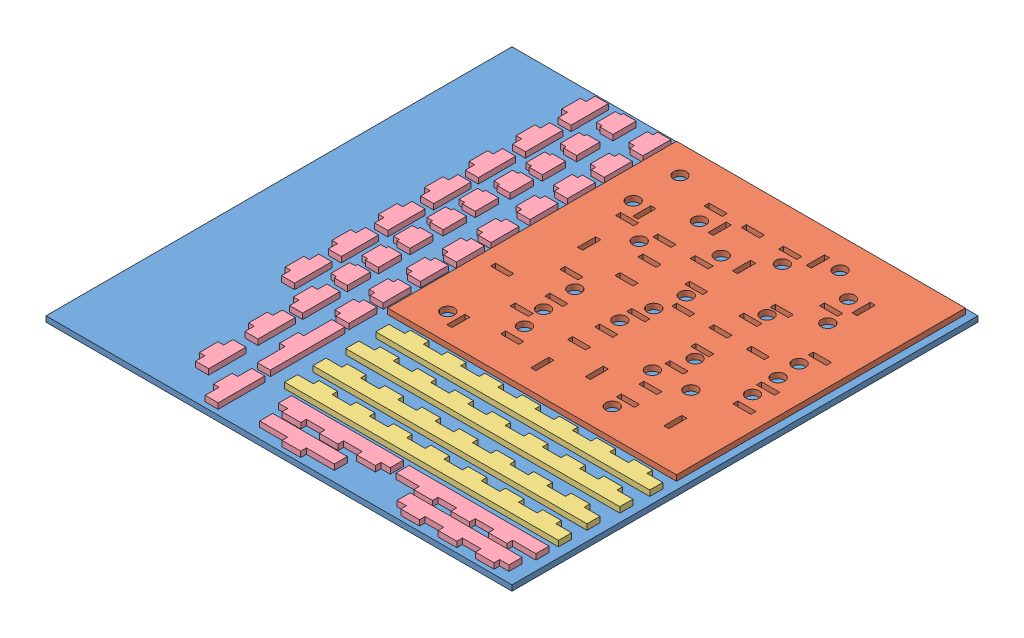
SolidWorks assembly Layout_Assly, configuration Default. Lengths in mm.
Overall size (500 12 500).
40 component instances, 4 part files, 44 mates.
Components (placement in the parent):
- Part2-1: Part2 [Default] at origin size (500 6 500)
- BasePlate-1: BasePlate [Default] at (492.029 6 -494.4537) x (-1 0 0) z (0 0 -1) size (310 6 310)
- SIdePlate-1: SIdePlate [Default] at (344.8244 12 -170.014) x (1 0 0) z (0 -1 0) size (294 20 6)
- SIdePlate-2: SIdePlate [Default] at (344.2023 12 -138.4405) x (1 0 0) z (0 -1 0) size (294 20 6)
- SIdePlate-3: SIdePlate [Default] at (342.5749 12 -104.9025) x (1 0 0) z (0 -1 0) size (294 20 6)
- SIdePlate-4: SIdePlate [Default] at (342.6836 12 -74.261) x (1 0 0) z (0 -1 0) size (294 20 6)
- Partition-1: Partition [Default] at (163.5434 12 -492.808) x (0 -1 0) z (0 0 1) size (6 20 30)
- Partition-2: Partition [Default] at (162.8997 12 -452.1256) x (0 -1 0) z (0 0 1) size (6 20 30)
- Partition-3: Partition [Default] at (162.8487 12 -412.6126) x (0 -1 0) z (0 0 1) size (6 20 30)
- Partition-4: Partition [Default] at (162.2578 12 -373.1005) x (0 -1 0) z (0 0 1) size (6 20 30)
- Partition-5: Partition [Default] at (162.7722 12 -330.7673) x (0 -1 0) z (0 0 1) size (6 20 30)
- Partition-6: Partition [Default] at (162.2941 12 -294.0403) x (0 -1 0) z (0 0 1) size (6 20 30)
- Partition-7: Partition [Default] at (160.9984 12 -256.6845) x (0 -1 0) z (0 0 1) size (6 20 30)
- Partition-8: Partition [Default] at (160.886 12 -216.9444) x (0 -1 0) z (0 0 1) size (6 20 30)
- Partition-9: Partition [Default] at (161.5652 12 -179.4132) x (0 -1 0) z (0 0 1) size (6 20 30)
- Partition-10: Partition [Width_150mm] at (489.8619 6 -35.7855) x (0 1 0) z (-1 0 0) size (6 20 150)
- Partition-11: Partition [Width_120mm] at (331.87 6 -37.5014) x (0 1 0) z (-1 0 0) size (6 20 120)
- Partition-12: Partition [Width_120mm] at (485.9067 6 -10.8609) x (0 1 0) z (-1 0 0) size (6 20 120)
- Partition-13: Partition [Width_80mm] at (162.858 12 -143.8335) x (0 -1 0) z (0 0 1) size (6 20 80)
- Partition-14: Partition [Width_80mm] at (298.3896 6 -10.9079) x (0 1 0) z (-1 0 0) size (6 20 80)
- Partition-15: Partition [width_50mm] at (165.2881 12 -55.4645) x (0 -1 0) z (0 0 1) size (6 20 50)
- Partition-16: Partition [Width_25mm] at (127.6871 12 -491.5944) x (0 -1 0) z (0 0 1) size (6 20 25)
- Partition-17: Partition [Width_25mm] at (127.7224 12 -452.5904) x (0 -1 0) z (0 0 1) size (6 20 25)
- Partition-18: Partition [Width_25mm] at (127.2263 12 -416.2576) x (0 -1 0) z (0 0 1) size (6 20 25)
- Partition-19: Partition [Width_25mm] at (127.0085 12 -382.0514) x (0 -1 0) z (0 0 1) size (6 20 25)
- Partition-20: Partition [Width_25mm] at (125.1472 12 -346.4351) x (0 -1 0) z (0 0 1) size (6 20 25)
- Partition-21: Partition [Width_25mm] at (125.0837 12 -312.1334) x (0 -1 0) z (0 0 1) size (6 20 25)
- Partition-22: Partition [Width_25mm] at (124.6156 12 -276.8588) x (0 -1 0) z (0 0 1) size (6 20 25)
- Partition-23: Partition [Width_25mm] at (125.4179 12 -242.1872) x (0 -1 0) z (0 0 1) size (6 20 25)
- Partition-24: Partition [Width_25mm] at (125.4406 12 -208.8491) x (0 -1 0) z (0 0 1) size (6 20 25)
- Partition-25: Partition [Width_40mm] at (127.2199 12 -174.1968) x (0 -1 0) z (0 0 1) size (6 20 40)
- Partition-26: Partition [Width_40mm] at (127.3475 12 -126.1339) x (0 -1 0) z (0 0 1) size (6 20 40)
- Partition-27: Partition [Width_40mm] at (96.5799 12 -492.7639) x (0 -1 0) z (0 0 1) size (6 20 40)
- Partition-28: Partition [Width_40mm] at (96.8462 12 -443.668) x (0 -1 0) z (0 0 1) size (6 20 40)
- Partition-29: Partition [Width_40mm] at (95.6032 12 -394.3264) x (0 -1 0) z (0 0 1) size (6 20 40)
- Partition-30: Partition [Width_40mm] at (95.781 12 -346.2225) x (0 -1 0) z (0 0 1) size (6 20 40)
- Partition-31: Partition [Width_40mm] at (96.0529 12 -296.6662) x (0 -1 0) z (0 0 1) size (6 20 40)
- Partition-32: Partition [Width_40mm] at (95.3483 12 -247.5018) x (0 -1 0) z (0 0 1) size (6 20 40)
- Partition-33: Partition [Width_40mm] at (128.4442 12 -72.1397) x (0 -1 0) z (0 0 1) size (6 20 40)
- Partition-34: Partition [Width_40mm] at (95.0635 12 -197.5849) x (0 -1 0) z (0 0 1) size (6 20 40)
Mates (geometry in assembly coordinates):
- Coincident1: coincident anti-aligned: plane of Part2-1 through (0 6 0) normal (0 1 0); plane of BasePlate-1 through (492.029 6 -494.4537) normal (0 -1 0)
- Parallel1: parallel aligned: plane of Part2-1 through (0 6 -500) normal (0 0 -1); plane of BasePlate-1 through (492.029 12 -494.4537) normal (0 0 -1)
- Coincident2: coincident anti-aligned: plane of Part2-1 through (0 6 0) normal (0 1 0); plane of SIdePlate-1 through (344.8244 6 -170.014) normal (0 -1 0)
- Coincident3: coincident anti-aligned: plane of Part2-1 through (0 6 0) normal (0 1 0); plane of SIdePlate-2 through (344.2023 6 -138.4405) normal (0 -1 0)
- Coincident4: coincident anti-aligned: plane of Part2-1 through (0 6 0) normal (0 1 0); plane of SIdePlate-3 through (342.5749 6 -104.9025) normal (0 -1 0)
- Coincident5: coincident anti-aligned: plane of Part2-1 through (0 6 0) normal (0 1 0); plane of SIdePlate-4 through (342.6836 6 -74.261) normal (0 -1 0)
- Coincident6: coincident anti-aligned: plane of Part2-1 through (0 6 0) normal (0 1 0); plane of Partition-1 through (163.5434 6 -462.808) normal (0 -1 0)
- Coincident7: coincident anti-aligned: plane of Part2-1 through (0 6 0) normal (0 1 0); plane of Partition-2 through (162.8997 6 -422.1256) normal (0 -1 0)
- Coincident8: coincident anti-aligned: plane of Part2-1 through (0 6 0) normal (0 1 0); plane of Partition-3 through (162.8487 6 -382.6126) normal (0 -1 0)
- Coincident9: coincident anti-aligned: plane of Part2-1 through (0 6 0) normal (0 1 0); plane of Partition-4 through (162.2578 6 -343.1005) normal (0 -1 0)
- Coincident10: coincident anti-aligned: plane of Part2-1 through (0 6 0) normal (0 1 0); plane of Partition-5 through (162.7722 6 -300.7673) normal (0 -1 0)
- Coincident11: coincident anti-aligned: plane of Part2-1 through (0 6 0) normal (0 1 0); plane of Partition-6 through (162.2941 6 -264.0403) normal (0 -1 0)
- Coincident12: coincident anti-aligned: plane of Part2-1 through (0 6 0) normal (0 1 0); plane of Partition-7 through (160.9984 6 -226.6845) normal (0 -1 0)
- Coincident13: coincident anti-aligned: plane of Part2-1 through (0 6 0) normal (0 1 0); plane of Partition-8 through (160.886 6 -186.9444) normal (0 -1 0)
- Coincident14: coincident anti-aligned: plane of Part2-1 through (0 6 0) normal (0 1 0); plane of Partition-9 through (161.5652 6 -149.4132) normal (0 -1 0)
- Coincident15: coincident anti-aligned: plane of Part2-1 through (0 6 0) normal (0 1 0); plane of Partition-10 through (339.8619 6 -35.7855) normal (0 -1 0)
- Parallel2: parallel anti-aligned: plane of Part2-1 through (500 6 0) normal (1 0 0); plane of Partition-10 through (339.8619 6 -35.7855) normal (-1 0 0)
- Parallel3: parallel anti-aligned: plane of Part2-1 through (500 6 0) normal (1 0 0); plane of Partition-11 through (211.87 6 -37.5014) normal (-1 0 0)
- Coincident20: coincident anti-aligned: plane of Part2-1 through (0 6 0) normal (0 1 0); plane of Partition-11 through (211.87 6 -37.5014) normal (0 -1 0)
- Parallel4: parallel anti-aligned: plane of Part2-1 through (500 6 0) normal (1 0 0); plane of Partition-12 through (365.9067 6 -10.8609) normal (-1 0 0)
- Coincident22: coincident anti-aligned: plane of Part2-1 through (0 6 0) normal (0 1 0); plane of Partition-12 through (365.9067 6 -10.8609) normal (0 -1 0)
- Parallel6: parallel anti-aligned: plane of Part2-1 through (500 6 0) normal (1 0 0); plane of Partition-14 through (218.3896 6 -10.9079) normal (-1 0 0)
- Coincident24: coincident anti-aligned: plane of Part2-1 through (0 6 0) normal (0 1 0); plane of Partition-14 through (218.3896 6 -10.9079) normal (0 -1 0)
- Coincident25: coincident anti-aligned: plane of Part2-1 through (0 6 0) normal (0 1 0); plane of Partition-13 through (162.858 6 -63.8335) normal (0 -1 0)
- Coincident26: coincident anti-aligned: plane of Part2-1 through (0 6 0) normal (0 1 0); plane of Partition-15 through (165.2881 6 -5.4645) normal (0 -1 0)
- Coincident27: coincident anti-aligned: plane of Part2-1 through (0 6 0) normal (0 1 0); plane of Partition-16 through (127.6871 6 -466.5944) normal (0 -1 0)
- Coincident28: coincident anti-aligned: plane of Part2-1 through (0 6 0) normal (0 1 0); plane of Partition-17 through (127.7224 6 -427.5904) normal (0 -1 0)
- Coincident29: coincident anti-aligned: plane of Part2-1 through (0 6 0) normal (0 1 0); plane of Partition-18 through (127.2263 6 -391.2576) normal (0 -1 0)
- Coincident30: coincident anti-aligned: plane of Part2-1 through (0 6 0) normal (0 1 0); plane of Partition-19 through (127.0085 6 -357.0514) normal (0 -1 0)
- Coincident31: coincident anti-aligned: plane of Part2-1 through (0 6 0) normal (0 1 0); plane of Partition-20 through (125.1472 6 -321.4351) normal (0 -1 0)
- Coincident32: coincident anti-aligned: plane of Part2-1 through (0 6 0) normal (0 1 0); plane of Partition-21 through (125.0837 6 -287.1334) normal (0 -1 0)
- Coincident33: coincident anti-aligned: plane of Part2-1 through (0 6 0) normal (0 1 0); plane of Partition-22 through (124.6156 6 -251.8588) normal (0 -1 0)
- Coincident34: coincident anti-aligned: plane of Part2-1 through (0 6 0) normal (0 1 0); plane of Partition-23 through (125.4179 6 -217.1872) normal (0 -1 0)
- Coincident35: coincident anti-aligned: plane of Part2-1 through (0 6 0) normal (0 1 0); plane of Partition-24 through (125.4406 6 -183.8491) normal (0 -1 0)
- Coincident36: coincident anti-aligned: plane of Part2-1 through (0 6 0) normal (0 1 0); plane of Partition-25 through (127.2199 6 -134.1968) normal (0 -1 0)
- Coincident37: coincident anti-aligned: plane of Part2-1 through (0 6 0) normal (0 1 0); plane of Partition-26 through (127.3475 6 -86.1339) normal (0 -1 0)
- Coincident38: coincident anti-aligned: plane of Part2-1 through (0 6 0) normal (0 1 0); plane of Partition-27 through (96.5799 6 -452.7639) normal (0 -1 0)
- Coincident39: coincident anti-aligned: plane of Part2-1 through (0 6 0) normal (0 1 0); plane of Partition-28 through (96.8462 6 -403.668) normal (0 -1 0)
- Coincident40: coincident anti-aligned: plane of Part2-1 through (0 6 0) normal (0 1 0); plane of Partition-29 through (95.6032 6 -354.3264) normal (0 -1 0)
- Coincident41: coincident anti-aligned: plane of Part2-1 through (0 6 0) normal (0 1 0); plane of Partition-30 through (95.781 6 -306.2225) normal (0 -1 0)
- Coincident42: coincident anti-aligned: plane of Part2-1 through (0 6 0) normal (0 1 0); plane of Partition-31 through (96.0529 6 -256.6662) normal (0 -1 0)
- Coincident43: coincident anti-aligned: plane of Part2-1 through (0 6 0) normal (0 1 0); plane of Partition-32 through (95.3483 6 -207.5018) normal (0 -1 0)
- Coincident44: coincident anti-aligned: plane of Part2-1 through (0 6 0) normal (0 1 0); plane of Partition-33 through (128.4442 6 -32.1397) normal (0 -1 0)
- Coincident45: coincident anti-aligned: plane of Part2-1 through (0 6 0) normal (0 1 0); plane of Partition-34 through (95.0635 6 -157.5849) normal (0 -1 0)
